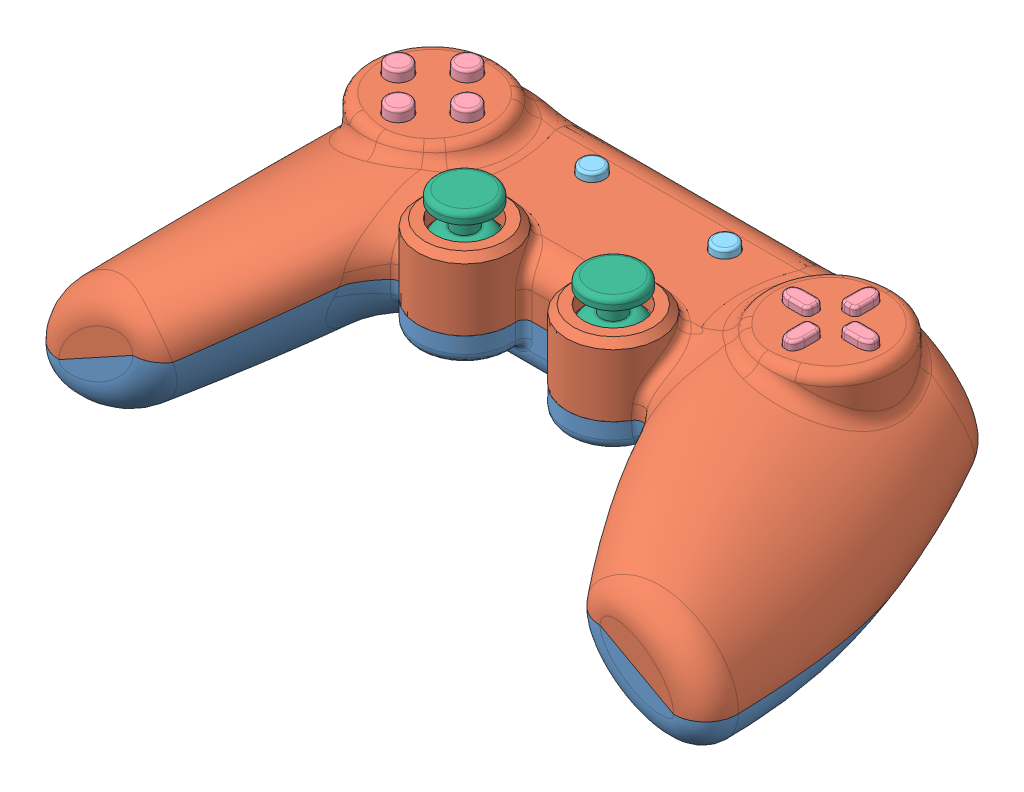
SolidWorks assembly 03_02_Create an Assembly, configuration Default. Lengths in mm.
Overall size (261.17 83.89 131.86).
9 component instances, 6 part files, 12 mates.
Components (placement in the parent):
- 03_01_Split the Controller into Two Halves_Bottom-1: 03_01_Split the Controller into Two Halves_Bottom [Default] at origin size (261.17 55.59 131.86)
- 03_01_Split the Controller into Two Halves_Top-1: 03_01_Split the Controller into Two Halves_Top [Default] at origin size (261.17 72.3 131.86)
- 05_01_Create the PCB Model-5: 05_01_Create the PCB Model [Default] at (0 0.8 0) size (190 11.6 50)
- 06_01_Model the Buttons-3: 06_01_Model the Buttons [Buttons] at (-75 23 0) size (38 7 38)
- 06_01_Model the Buttons-4: 06_01_Model the Buttons [D-Pad] at (75 23 0) x (-1 0 0) z (0 0 -1) size (38 6.02 38)
- 06_05_Model and Add the Centre Buttons-1: 06_05_Model and Add the Centre Buttons [Default] at (-25 17 -10) size (14 6 14)
- 06_05_Model and Add the Centre Buttons-2: 06_05_Model and Add the Centre Buttons [Default] at (25 17 -10) x (-1 0 0) z (0 0 -1) size (14 6 14)
- 07_01_Model the Joystick-7: 07_01_Model the Joystick [Default] at (-28 1.6 35) size (22 34 22)
- 07_01_Model the Joystick-8: 07_01_Model the Joystick [Default] at (28 1.6 35) x (-1 0 0) z (0 0 -1) size (22 34 22)
Mates (geometry in assembly coordinates):
- Coincident9: coincident aligned: plane of PCB-5 through (0 0.8 0) normal (1 0 0)
- Coincident10: coincident aligned: plane of PCB-5 through (0 0.8 0) normal (0 0 1)
- Coincident11: coincident anti-aligned: plane of Controller Bottom-1 through (54.3696 0 -30.01) normal (0 1 0); plane of PCB-5 through (0 0 0) normal (0 -1 0)
- Coincident14: coincident aligned: plane of Controller Buttons-3 through (-75 23 0) normal (0 0 1)
- Distance3: distance = 75 mm aligned: plane of Controller Buttons-3 through (-75 23 0) normal (1 0 0)
- Coincident15: coincident anti-aligned: plane of Controller Top-1 through (-75 24 0) normal (0 -1 0); plane of Controller Buttons-3 through (-75 24 0) normal (0 1 0)
- Distance4: distance = 10 mm aligned: plane of Centre Button-1 through (-25 17 -10) normal (0 0 1)
- Distance5: distance = 25 mm aligned: plane of Centre Button-1 through (-25 17 -10) normal (1 0 0)
- Coincident16: coincident: plane of ? through (0 18 0) normal (0 -1 0); plane of 06_05_Model and Add the Centre Buttons-1 through (-32 18 -10) normal (0 1 0)
- Concentric5: concentric aligned: cylinder of Controller Top-1 through (-28 -10 35) axis (0 1 0) radius 17.5; circle of Joystick-7
- Parallel4: parallel aligned: plane of Joystick-7 through (-28 1.6 35) normal (0 0 1)
- Coincident19: coincident anti-aligned: plane of PCB-5 through (0 1.6 0) normal (0 1 0); plane of Joystick-7 through (-28 1.6 35) normal (0 -1 0)
